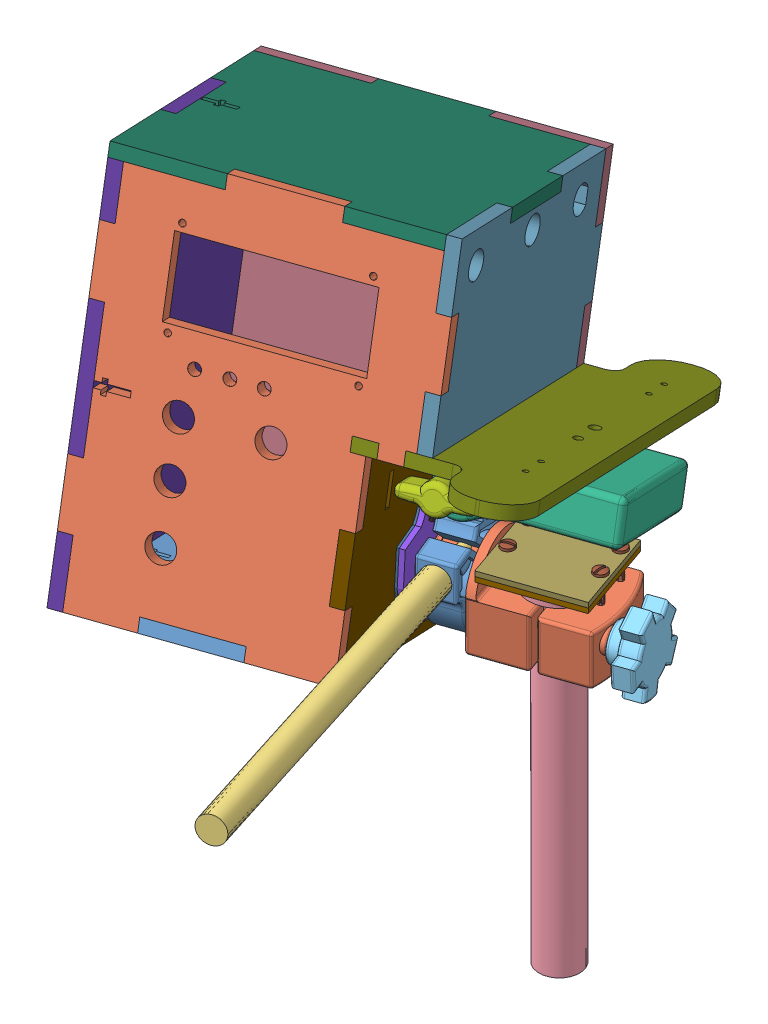
SolidWorks assembly Tripod, configuration Default. Lengths in mm.
Overall size (318.64 373.1 361.15).
29 component instances, 21 part files, 49 mates.
Components (placement in the parent):
- Pitch Platform-1: Pitch Platform [Default] at (-4.0368 -23.4921 -273.1076) x (0.315622 0.289741 0.903567) z (-0.944062 0 0.329767) size (53.67 64.26 21.84)
- Pitch Disk-1: Pitch Disk [Default] at (-19.1471 -23.49 -267.8403) x (0.329767 0 0.944062) z (-0.944062 0 0.329767) size (44.62 39.88 69.6)
- Pitch Arm-1: Pitch Arm [Default] at (-18.6907 -13.0745 -290.7963) x (0.252963 -0.966553 -0.04226) z (0.329433 0.044983 0.943107) size (12.19 12.19 218.69)
- Yaw Wheel-1: Yaw Wheel [Default] at (19.939 -171.953 -281.4933) x (0.098042 0 -0.995182) z (0.995182 0 0.098042) size (28.96 159.26 28.96)
- Yaw Screw-1: Yaw Screw [Default] at (6.0778 -26.411 -264.9478) x (0.321115 0.227557 0.919295) z (0.944062 0 -0.329767) size (35.75 34.85 59.79)
- Roll Base-1: Roll Base [Default] at (-20.9514 3.5302 -304.9707) x (-0.944062 0 0.329767) z (-0.095547 0.957105 -0.273533) size (71.12 51.82 24.38)
- Roll Screw-1: Roll Screw [Default] at (-22.9485 3.8982 -302.9855) x (0.115412 -0.956893 0.266526) z (0.315622 0.289741 0.903567) size (13.21 30.25 64.67)
- Pitch Mounts-1: Pitch Mounts [Default] at (-20.042 -32.2854 -258.8487) x (-0.315622 -0.289741 -0.903567) z (0.944062 0 -0.329767) size (53.93 43.31 2.29)
- Yaw Mount with hole-1: Yaw Mount with hole [Default] at (6.1319 -11.425 -255.55) x (-0.944062 0 0.329767) z (-0.329767 0 -0.944062) size (41.91 2.29 39.88)
- Pitch Mount no hole-1: Pitch Mount no hole [Default] at (-22.2001 -32.2854 -258.0948) x (-0.315622 -0.289741 -0.903567) z (0.944062 0 -0.329767) size (53.93 43.31 2.29)
- binding head screw_ai-7: binding head screw_ai [SL-BHMS 0.112-40x0.5x0.5-S] at (-27.9061 -29.9639 -248.6426) x (0.944062 0 -0.329767) z (0.329161 -0.060594 0.942328) size (14.41 5.97 5.97)
- binding head screw_ai-8: binding head screw_ai [SL-BHMS 0.112-40x0.5x0.5-S] at (-39.7621 -11.8535 -282.584) x (0.944062 0 -0.329767) z (0.13936 -0.906315 0.398963) size (14.41 5.97 5.97)
- binding head screw_ai-9: binding head screw_ai [SL-BHMS 0.112-40x0.5x0.5-S] at (-31.3844 -1.9136 -258.6002) x (0.944062 0 -0.329767) z (0.329758 0.007499 0.944036) size (14.41 5.97 5.97)
- binding head screw_ai-10: binding head screw_ai [SL-BHMS 0.112-40x0.5x0.5-S] at (-36.558 -34.2181 -273.4113) x (0.944062 0 -0.329767) z (0.32331 -0.196917 0.925578) size (14.41 5.97 5.97)
- Yaw Mount-2: Yaw Mount [Default] at (6.1319 -9.139 -255.55) x (-0.944062 0 0.329767) z (-0.329767 0 -0.944062) size (41.91 2.29 39.88)
- binding head screw_ai-11: binding head screw_ai [SL-BHMS 0.112-40x0.75x0.75-S] at (36.405 -5.1258 -284.4199) x (0 -1 0) z (0 0 1) size (20.76 5.97 5.97)
- binding head screw_ai-12: binding head screw_ai [SL-BHMS 0.112-40x0.75x0.75-S] at (31.3793 -5.1258 -298.8074) x (0 -1 0) z (0 0 1) size (20.76 5.97 5.97)
- binding head screw_ai-13: binding head screw_ai [SL-BHMS 0.112-40x0.75x0.75-S] at (4.0331 -5.1258 -273.1122) x (0 -1 0) z (-0.924225 0 0.381849) size (20.76 5.97 5.97)
- binding head screw_ai-14: binding head screw_ai [SL-BHMS 0.112-40x0.75x0.75-S] at (-1.4114 -5.1258 -288.6987) x (0 -1 0) z (0 0 1) size (20.76 5.97 5.97)
- Box-1: Box [Default] at (22.3083 516.5826 -321.7655) x (-0.143658 0.910757 0.387149) z (0.828355 0.324711 -0.456498) size (232.68 217.02 202.45)
  - Long Side-1: Long Side [Default] at (-407.1157 51.7843 -241.4115) x (0.263291 -0.247013 -0.932557) z (0.568357 0.820809 -0.056948) size (129.95 166.52 5.79)
  - Short Side-1: Short Side [Default] at (-388.3684 115.9809 -189.6606) x (-0.568357 -0.820809 0.056948) z (-0.263291 0.247013 0.932557) size (120.8 83.97 5.79)
  - Top-1: Top [Default] at (-340.0573 79.738 -229.883) x (0.263291 -0.247013 -0.932557) z (-0.779518 0.515031 -0.356503) size (129.95 120.8 5.79)
  - Bottom-1: Bottom [Default] at (-418.7233 135.3778 -213.0377) x (0.263291 -0.247013 -0.932557) z (0.779518 -0.515031 0.356503) size (74.07 171.6 5.79)
  - Short Side 2-1: Short Side 2 [Default] at (-387.854 106.5709 -320.1571) x (0.568357 0.820809 -0.056948) z (-0.263291 0.247013 0.932557) size (120.8 166.52 5.8)
  - Inside L-1: Inside L [Default] at (-446.2666 152.9171 -235.1289) x (-0.779518 0.515031 -0.356503) z (0.263291 -0.247013 -0.932557) size (88.34 120.8 5.79)
  - Low Bottom-1: Low Bottom [Default] at (-466.728 162.5597 -300.3579) x (0.263291 -0.247013 -0.932557) z (0.779518 -0.515031 0.356503) size (106.12 120.8 5.79)
  - Long Side 2-1: Long Side 2 [Default] at (-341.7483 146.1866 -247.9611) x (0.263291 -0.247013 -0.932557) z (0.568357 0.820809 -0.056948) size (129.95 166.52 5.79)
- Arduino UNO-1: Arduino UNO [Default] at (-73.2398 -45.6197 -249.1012) x (-0.315622 -0.289741 -0.903567) z (0.944062 0 -0.329767) size (74.8 12.1 53.3)
Mates (geometry in assembly coordinates):
- Concentric1: concentric anti-aligned: cylinder of Pitch Platform-1 through (-19.1471 -23.49 -267.8403) axis (0.944062 0 -0.329767) radius 13.335; cylinder of Pitch Disk-1 through (-4.0402 -23.49 -273.1172) axis (-0.944062 0 0.329767) radius 13.335
- Coincident1: coincident anti-aligned: plane of Pitch Platform-1 through (-28.0068 -24.4127 -293.204) normal (-0.944062 0 0.329767); plane of Pitch Disk-1 through (-19.1471 -23.49 -267.8403) normal (0.944062 0 -0.329767)
- Concentric2: concentric anti-aligned: cylinder of Pitch Platform-1 through (-16.3812 -12.7592 -284.1847) axis (0.329433 0.044983 0.943107) radius 3.048; cylinder of Pitch Arm-1 through (-3.5453 -11.0065 -247.4379) axis (-0.329433 -0.044983 -0.943107) radius 2.921
- Coincident2: coincident anti-aligned: plane of Pitch Platform-1 through (-3.5453 -11.0065 -247.4379) normal (0.329433 0.044983 0.943107); plane of Pitch Arm-1 through (-3.5453 -11.0065 -247.4379) normal (-0.329433 -0.044983 -0.943107)
- Concentric4: concentric anti-aligned: cylinder of Pitch Disk-1 through (19.939 -66.289 -281.4933) axis (0 1 0) radius 9.652; cylinder of Yaw Wheel-1 through (19.939 -18.029 -281.4933) axis (0 -1 0) radius 9.525
- Distance1: distance = 1.27 mm anti-aligned: plane of Pitch Disk-1 through (-40.8593 -19.299 -239.1356) normal (0 1 0); plane of Yaw Wheel-1 through (19.939 -18.029 -281.4933) normal (0 -1 0)
- Concentric5: concentric aligned: cylinder of Yaw Screw-1 through (48.0414 -26.411 -279.6059) axis (-0.944062 0 0.329767) radius 2.921; cylinder of Pitch Disk-1 through (47.5627 -26.411 -279.4387) axis (-0.944062 0 0.329767) radius 3.175
- Distance2: distance = 0.508 mm anti-aligned: plane of Yaw Screw-1 through (48.0414 -26.411 -279.6059) normal (-0.944062 0 0.329767); plane of Pitch Disk-1 through (47.5618 -51.8705 -279.4384) normal (0.944062 0 -0.329767)
- Concentric6: concentric anti-aligned: cylinder of Pitch Platform-1 through (-22.5829 4.2338 -301.9389) axis (0.315622 0.289741 0.903567) radius 2.9464; cylinder of Roll Base-1 through (-6.9951 18.5434 -257.3139) axis (-0.315622 -0.289741 -0.903567) radius 2.921
- Width1: width aligned: plane of Roll Base-1 through (-20.9514 3.5302 -304.9707) normal (-0.315622 -0.289741 -0.903567); plane of Roll Base-1 through (-4.5971 18.5434 -258.1515) normal (0.315622 0.289741 0.903567); plane of Pitch Platform-1 through (-26.1742 -1.4174 -287.9575) normal (-0.315622 -0.289741 -0.903567); plane of Pitch Platform-1 through (-17.5783 6.4737 -263.3491) normal (0.315622 0.289741 0.903567)
- Concentric7: concentric aligned: cylinder of Roll Screw-1 through (-6.5942 18.9114 -256.1663) axis (-0.315622 -0.289741 -0.903567) radius 2.794; cylinder of Roll Base-1 through (-6.9951 18.5434 -257.3139) axis (-0.315622 -0.289741 -0.903567) radius 2.921
- Distance3: distance = 1.27 mm anti-aligned: plane of Roll Base-1 through (-4.5971 18.5434 -258.1515) normal (0.315622 0.289741 0.903567); plane of Roll Screw-1 through (-6.5942 18.9114 -256.1663) normal (-0.315622 -0.289741 -0.903567)
- Parallel12: parallel anti-aligned: plane of Pitch Platform-1 through (-28.0068 -24.4127 -293.204) normal (-0.944062 0 0.329767); plane of Pitch Mounts-1 through (-22.9397 -16.9752 -267.1441) normal (0.944062 0 -0.329767)
- Coincident35: coincident aligned: plane of Yaw Mount with hole-1 through (6.1319 -9.139 -255.55) normal (0.329767 0 0.944062); plane of Pitch Disk-1 through (-40.8593 -19.299 -239.1356) normal (0.329767 0 0.944062)
- Coincident37: coincident aligned: plane of Pitch Disk-1 through (-54.0098 -19.299 -276.7829) normal (-0.329767 0 -0.944062); plane of Yaw Mount with hole-1 through (32.5471 -9.139 -307.0178) normal (-0.329767 0 -0.944062)
- Coincident72: coincident anti-aligned: plane of Pitch Disk-1 through (-0.4433 -23.49 -274.3736) normal (0.944062 0 -0.329767); plane of Yaw Mount with hole-1 through (-7.0185 -9.139 -293.1973) normal (-0.944062 0 0.329767)
- Lock1: lock: unknown of ?; unknown of ?
- Coincident39: coincident aligned: plane of Pitch Mounts-1 through (-33.5432 -6.8798 -290.5678) normal (-0.095547 0.957105 -0.273533); plane of Pitch Platform-1 through (-28.2029 -7.2605 -293.7653) normal (-0.095547 0.957105 -0.273533)
- Coincident44: coincident aligned: line of Pitch Platform-1 through (-9.9931 -3.0164 -245.4854) axis (0.944062 0 -0.329767); line of Pitch Mounts-1 through (-16.9471 -3.0164 -243.0564) axis (0.944062 0 -0.329767)
- Distance12: distance = 3.81 mm anti-aligned: plane of Pitch Platform-1 through (-28.0068 -24.4127 -293.204) normal (-0.944062 0 0.329767); plane of Pitch Mounts-1 through (-22.9397 -16.9752 -267.1441) normal (0.944062 0 -0.329767)
- Coincident50: coincident anti-aligned: plane of Pitch Mount no hole-1 through (-25.0978 -16.9752 -266.3903) normal (0.944062 0 -0.329767); plane of Pitch Mounts-1 through (-25.0978 -16.9752 -266.3903) normal (-0.944062 0 0.329767)
- Coincident51: coincident aligned: plane of Pitch Mounts-1 through (-33.5432 -6.8798 -290.5678) normal (-0.095547 0.957105 -0.273533); plane of Pitch Mount no hole-1 through (-35.7013 -6.8798 -289.814) normal (-0.095547 0.957105 -0.273533)
- Coincident52: coincident aligned: plane of Pitch Mounts-1 through (-21.0078 -1.5102 -254.6814) normal (0.040038 0.992602 0.11462); plane of Pitch Mount no hole-1 through (-23.1659 -1.5102 -253.9276) normal (0.040038 0.992602 0.11462)
- Concentric12: concentric anti-aligned: cylinder of Pitch Mount no hole-1 through (-33.892 -11.8535 -284.6345) axis (0.944062 0 -0.329767) radius 1.397; cylinder of binding head screw_ai-8 through (-63.7412 -11.8535 -274.208) axis (-0.944062 0 0.329767) radius 1.4224
- Concentric13: concentric anti-aligned: cylinder of Pitch Mount no hole-1 through (-22.0361 -29.9639 -250.6931) axis (0.944062 0 -0.329767) radius 1.397; cylinder of binding head screw_ai-7 through (-51.8853 -29.9639 -240.2665) axis (-0.944062 0 0.329767) radius 1.4224
- Concentric14: concentric anti-aligned: cylinder of Pitch Mount no hole-1 through (-30.6879 -34.2181 -275.4617) axis (0.944062 0 -0.329767) radius 1.3622; cylinder of binding head screw_ai-10 through (-60.5371 -34.2181 -265.0352) axis (-0.944062 0 0.329767) radius 1.4224
- Concentric15: concentric anti-aligned: cylinder of Pitch Mount no hole-1 through (-25.5144 -1.9136 -260.6507) axis (0.944062 0 -0.329767) radius 1.397; cylinder of binding head screw_ai-9 through (-55.3636 -1.9136 -250.2242) axis (-0.944062 0 0.329767) radius 1.4224
- Coincident62: coincident aligned: plane of Yaw Mount-2 through (32.5471 -6.853 -307.0178) normal (-0.329767 0 -0.944062); plane of Yaw Mount with hole-1 through (32.5471 -9.139 -307.0178) normal (-0.329767 0 -0.944062)
- Coincident63: coincident aligned: plane of Yaw Mount with hole-1 through (45.6976 -9.139 -269.3705) normal (0.944062 0 -0.329767); plane of Yaw Mount-2 through (45.6976 -6.853 -269.3705) normal (0.944062 0 -0.329767)
- Coincident64: coincident anti-aligned: plane of Yaw Mount with hole-1 through (6.1319 -9.139 -255.55) normal (0 1 0); plane of Yaw Mount-2 through (6.1319 -9.139 -255.55) normal (0 -1 0)
- Concentric16: concentric anti-aligned: cylinder of Yaw Mount-2 through (4.0331 -6.853 -273.1122) axis (0 -1 0) radius 1.397; cylinder of binding head screw_ai-13 through (4.0331 20.2742 -273.1122) axis (0 1 0) radius 1.4224
- Concentric17: concentric anti-aligned: cylinder of Yaw Mount-2 through (-1.4114 -6.853 -288.6987) axis (0 -1 0) radius 1.397; cylinder of binding head screw_ai-14 through (-1.4114 20.2742 -288.6987) axis (0 1 0) radius 1.4224
- Concentric18: concentric anti-aligned: cylinder of Yaw Mount-2 through (31.3793 -6.853 -298.8074) axis (0 -1 0) radius 1.397; cylinder of binding head screw_ai-12 through (31.3793 20.2742 -298.8074) axis (0 1 0) radius 1.4224
- Concentric19: concentric anti-aligned: cylinder of Yaw Mount-2 through (36.405 -6.853 -284.4199) axis (0 -1 0) radius 1.397; cylinder of binding head screw_ai-11 through (36.405 20.2742 -284.4199) axis (0 1 0) radius 1.4224
- Coincident65: coincident anti-aligned: plane of Yaw Mount-2 through (6.1319 -6.853 -255.55) normal (0 1 0); plane of binding head screw_ai-13 through (4.5762 -6.853 -271.7976) normal (0 -1 0)
- Coincident66: coincident anti-aligned: plane of Yaw Mount-2 through (6.1319 -6.853 -255.55) normal (0 1 0); plane of binding head screw_ai-14 through (0.011 -6.853 -288.6987) normal (0 -1 0)
- Coincident67: coincident anti-aligned: plane of Yaw Mount-2 through (6.1319 -6.853 -255.55) normal (0 1 0); plane of binding head screw_ai-11 through (37.8274 -6.853 -284.4199) normal (0 -1 0)
- Coincident68: coincident anti-aligned: plane of Yaw Mount-2 through (6.1319 -6.853 -255.55) normal (0 1 0); plane of binding head screw_ai-12 through (32.8017 -6.853 -298.8074) normal (0 -1 0)
- Distance15: distance = 1.27 mm anti-aligned: plane of Yaw Wheel-1 through (19.939 -12.695 -281.4933) normal (0 1 0); plane of Yaw Mount with hole-1 through (6.1319 -11.425 -255.55) normal (0 -1 0)
- Concentric20: concentric anti-aligned: circle of Roll Base-1; cylinder of Box-1/Bottom-1 through (17.3485 42.5189 -302.1783) axis (0.095547 -0.957105 0.273533) radius 2.4003
- Distance16: distance = 5.842 mm anti-aligned: plane of Roll Base-1 through (28.0244 53.3325 -197.4973) normal (-0.095547 0.957105 -0.273533); plane of Box-1/Bottom-1 through (-20.7066 31.5147 -278.1744) normal (0.095547 -0.957105 0.273533)
- Parallel13: parallel anti-aligned: plane of Pitch Mount no hole-1 through (-27.2559 -16.9752 -265.6365) normal (-0.944062 0 0.329767); plane of Box-1/Inside L-1 through (-25.5522 -5.2185 -264.7029) normal (0.944062 0 -0.329767)
- Coincident74: coincident anti-aligned: plane of binding head screw_ai-7 through (-26.2471 -28.5441 -249.1308) normal (0.944062 0 -0.329767); plane of Box-1/Inside L-1 through (-31.0194 -5.2185 -262.7931) normal (-0.944062 0 0.329767)
- Coincident75: coincident anti-aligned: plane of binding head screw_ai-8 through (-37.7064 -11.2524 -281.9366) normal (0.944062 0 -0.329767); plane of Box-1/Inside L-1 through (-31.0194 -5.2185 -262.7931) normal (-0.944062 0 0.329767)
- Coincident76: coincident anti-aligned: plane of binding head screw_ai-9 through (-29.7573 -0.4913 -259.1799) normal (0.944062 0 -0.329767); plane of Box-1/Inside L-1 through (-31.0194 -5.2185 -262.7931) normal (-0.944062 0 0.329767)
- Coincident77: coincident anti-aligned: plane of binding head screw_ai-10 through (-34.835 -32.8235 -273.7164) normal (0.944062 0 -0.329767); plane of Box-1/Inside L-1 through (-31.0194 -5.2185 -262.7931) normal (-0.944062 0 0.329767)
- Width2: width aligned: plane of Arduino UNO-1 through (-54.8493 -40.8065 -273.7799) normal (0.944062 0 -0.329767); plane of Arduino UNO-1 through (-94.9166 -33.3892 -233.8305) normal (-0.944062 0 0.329767); plane of Box-1/Long Side-1 through (-140.3718 -12.3224 -289.1652) normal (-0.944062 0 0.329767); plane of Box-1/Long Side-1 through (-40.3957 -64.9951 -307.1973) normal (0.944062 0 -0.329767)
- Coincident78: coincident anti-aligned: plane of Box-1/Low Bottom-1 through (-71.9777 -41.9516 -236.7072) normal (-0.095547 0.957105 -0.273533); plane of Arduino UNO-1 through (-108.8146 -55.1811 -270.1307) normal (0.095547 -0.957105 0.273533)
- Distance17: distance = 6.35 mm anti-aligned: plane of Arduino UNO-1 through (-94.9663 -54.4031 -278.0949) normal (-0.315622 -0.289741 -0.903567); plane of Box-1/Long Side-1 through (-89.3132 55.8771 -322.4601) normal (0.315622 0.289741 0.903567)
